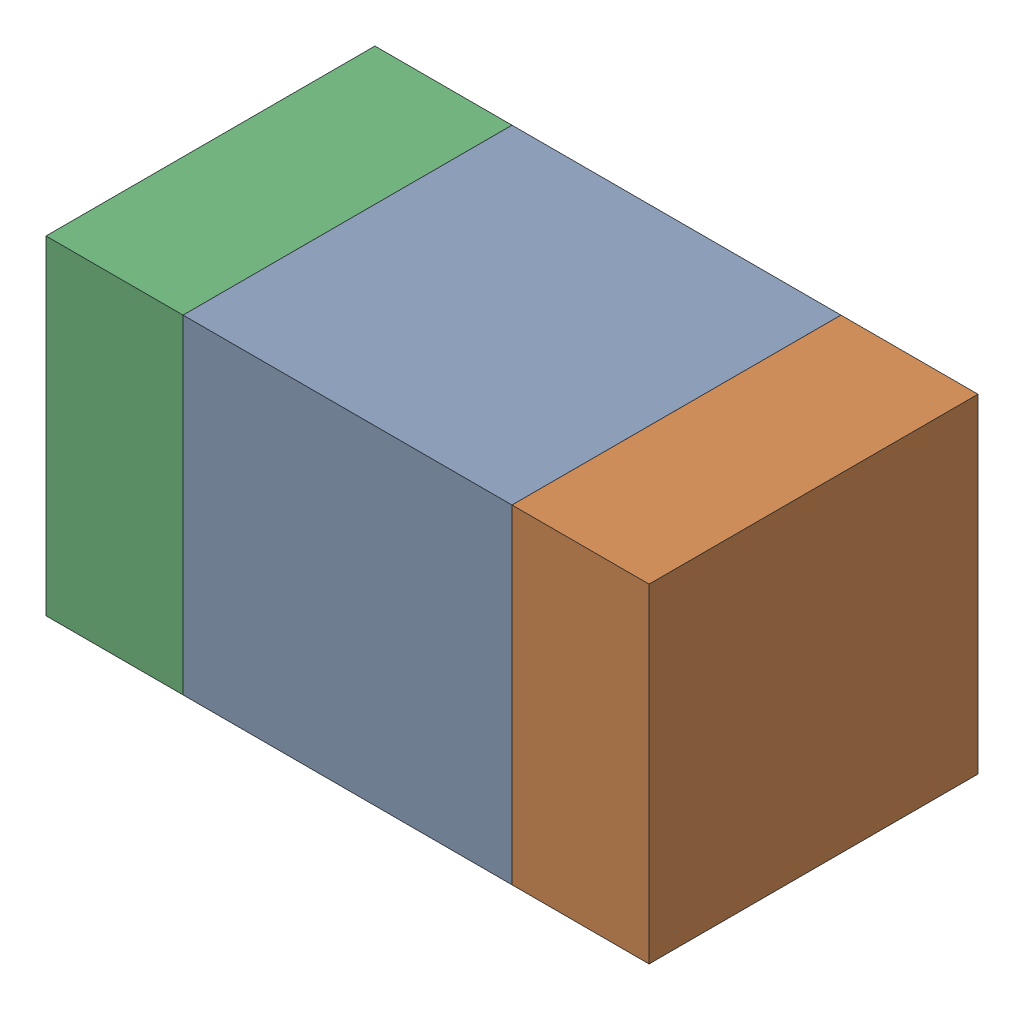
SolidWorks assembly C501_2PCB, configuration Default. Lengths in mm.
Overall size (1.1 0.6 0.6).
6 component instances, 2 part files, 0 mates.
Components (placement in the parent):
- 761606048-1: 761606048 [Default] at (146.7 89 0) size (0.6 0.6 0.6)
  - Extruded_9-1: Extruded_9 [Default] at origin size (0.6 0.6 0.6)
- 854785160-1: 854785160 [Default] at (147.125 89 0) size (0.25 0.6 0.6)
  - Extruded_19-1: Extruded_19 [Default] at origin size (0.25 0.6 0.6)
- 854785160-2: 854785160 [Default] at (146.275 89 0) size (0.25 0.6 0.6)
  - Extruded_19-1: Extruded_19 [Default] at origin size (0.25 0.6 0.6)
